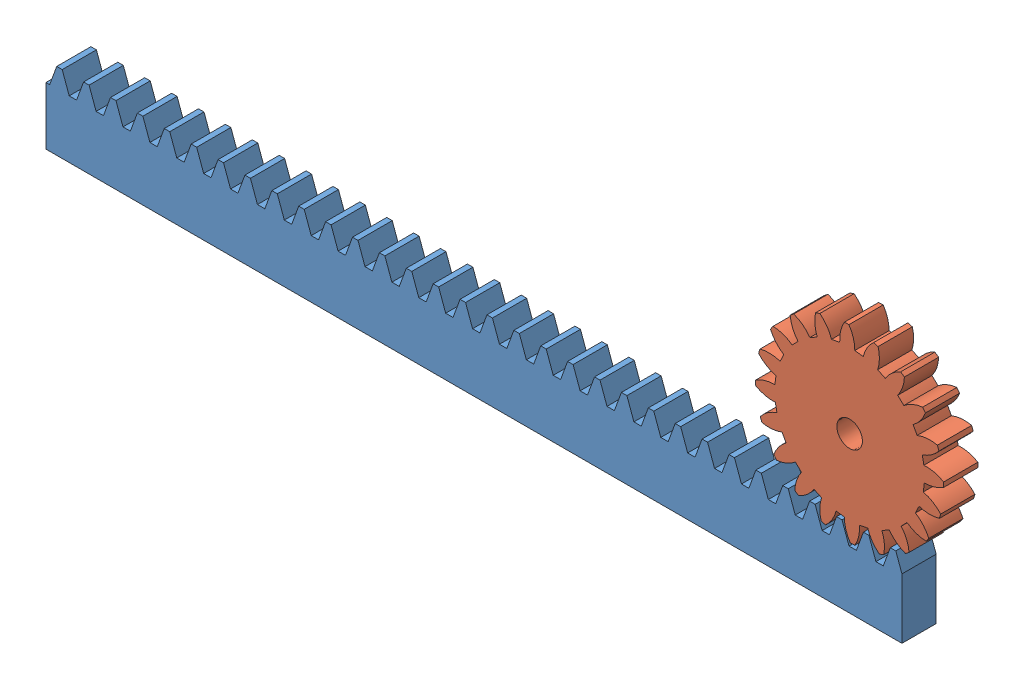
SolidWorks assembly Assem1, configuration Default. Lengths in mm.
Overall size (541.97 163.29 20).
2 component instances, 2 part files, 3 mates.
Components (placement in the parent):
- Metric - Rack-spur - rectangular 5M 20PA 20FW 40PH 500L---SAll-1: Metric - Rack-spur - rectangular 5M 20PA 20FW 40PH 500L---SAll [Metric - Rack-spur - rectangular 5M 20PA 20FW 40PH 500L---SAll] at (-201.5873 -39.0612 -4.2953) size (500 45 20)
- Metric - Spur gear 5M 20T 20PA 20FW ---S20N75H50L15N-1: Metric - Spur gear 5M 20T 20PA 20FW ---S20N75H50L15N [Metric - Spur gear 5M 20T 20PA 20FW ---S20N75H50L15N] at (267.8405 51.6888 -24.2953) x (0 0 1) z (-0.904818 0.425799 0) size (20 109.03 109.03)
Mates (geometry in assembly coordinates):
- Coincident1: coincident aligned: plane of Metric - Rack-spur - rectangular 5M 20PA 20FW 40PH 500L---SAll-1 through (-201.5873 5.9388 -4.2953) normal (0 0 1); plane of Metric - Spur gear 5M 20T 20PA 20FW ---S20N75H50L15N-1 through (258.5939 51.6888 -4.2953) normal (0 0 1)
- RackPinionMate1: rack pinion = 100 mm: line of Metric - Rack-spur - rectangular 5M 20PA 20FW 40PH 500L---SAll-1 through (-201.5873 -39.0612 -4.2953) axis (1 0 0); cylinder of Metric - Spur gear 5M 20T 20PA 20FW ---S20N75H50L15N-1 through (258.5939 51.6888 25.7048) axis (0 0 -1) radius 7.5
- Distance1: distance = 57 mm: plane of Metric - Rack-spur - rectangular 5M 20PA 20FW 40PH 500L---SAll-1 through (-89.4784 -5.3112 -24.2953) normal (0 1 0); line of Metric - Spur gear 5M 20T 20PA 20FW ---S20N75H50L15N-1 through (267.8405 51.6888 -4.2953) axis (0 0 -1)
